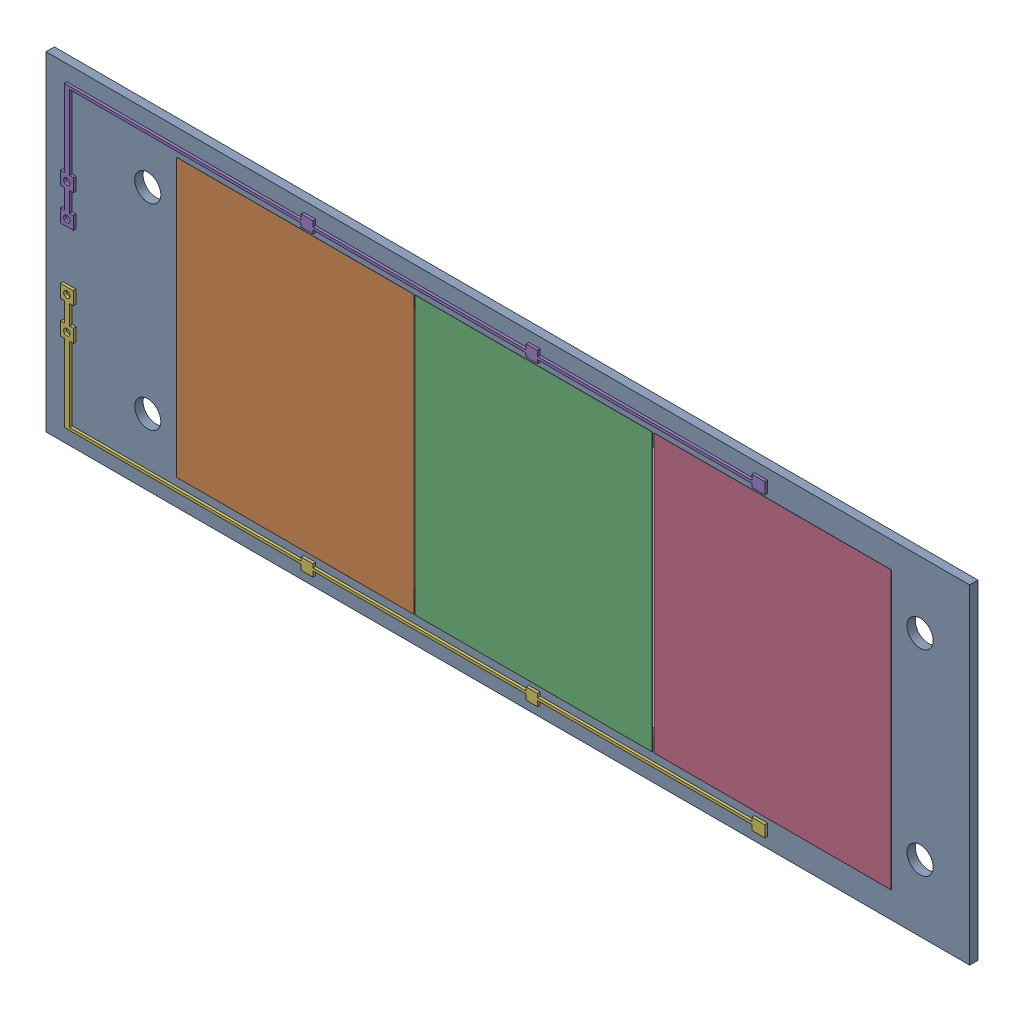
SolidWorks assembly GEM_assembly, configuration Default. Lengths in mm.
Overall size (354 126.2 4.2).
5 component instances, 3 part files, 0 mates.
Components (placement in the parent):
- GEM_PCB-1: GEM_PCB [Default] at (-6.7068 -5.2326 -2.5) size (354 126.2 3.2)
- GEM _10x10-1: GEM _10x10 [Default] at (-98.2068 -5.2326 0.75) x (0 -1 0) z (0 0 -1) size (106.2 91 0.05)
- GEM _10x10-2: GEM _10x10 [Default] at (-6.821 -5.2326 0.75) x (0 1 0) z (0 0 -1) size (106.2 91 0.05)
- GEM _10x10-3: GEM _10x10 [Default] at (84.7932 -5.2326 0.75) x (0 1 0) z (0 0 -1) size (106.2 91 0.05)
- GEM_connection-1: GEM_connection [Default] at (-6.7068 -5.2326 1.7) x (1 0 0) z (0 0 -1) size (269.98 118.27 1)
